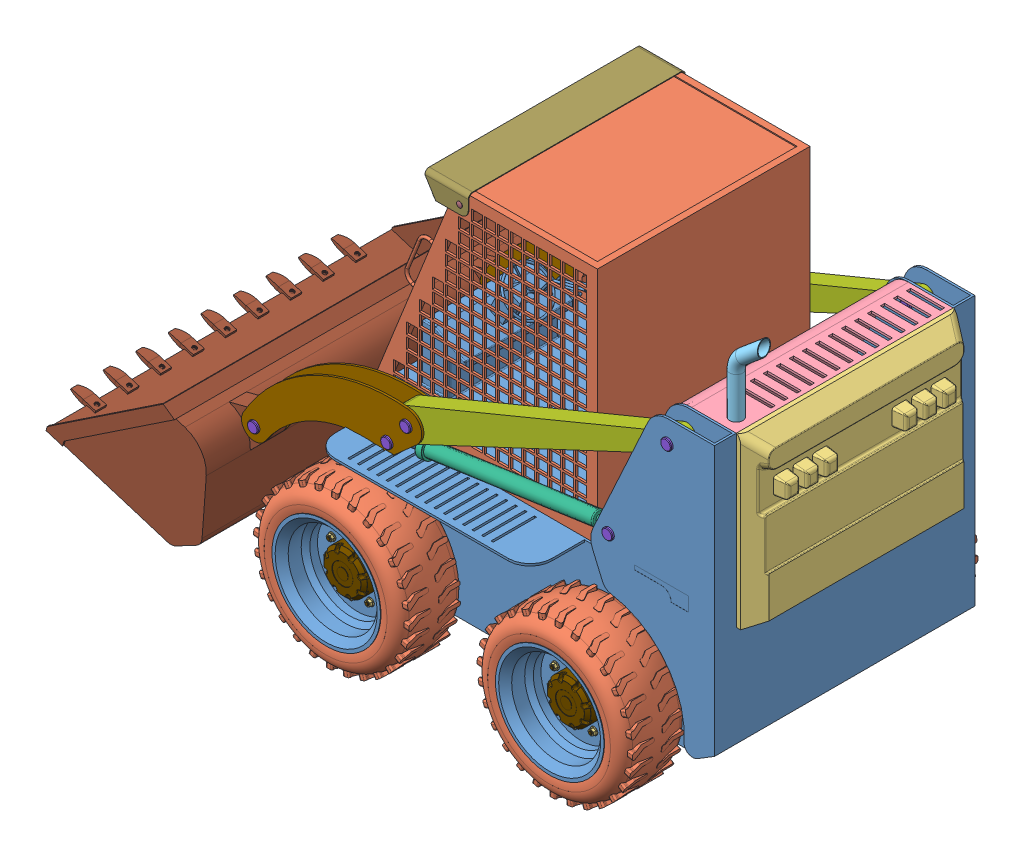
SolidWorks assembly Main Assem, configuration Default. Lengths in mm.
Overall size (3093.47 2132.66 1645.49).
96 component instances, 22 part files, 80 mates.
Components (placement in the parent):
- 1.Body-1: 1.Body [Default] at origin size (1800 1375 1500)
- 2.Cabin-1: 2.Cabin [Default] at (625 600 0) x (0 0 1) z (-1 0 0) size (980 1100 1050)
- 15.Back Support-1: 15.Back Support [Default] at (1150 600 0) size (350 1100 980) (hidden)
- 4.Backcover with light-1: 4.Backcover with light [Default] at (1850 987.5 0) x (0 0 1) z (-1 0 0) size (1000 775 130)
- 14.Backcover-1: 14.Backcover [Default] at (1260.667 789.9683 0) size (539.33 589.21 1000)
- 16.Exhaust Pipe-1: 16.Exhaust Pipe [Default] at (1735 1365 435) size (157.77 388.34 60)
- 11.Cylinder Rod-1: 11.Cylinder Rod [Default] at (830.4266 712.9576 550) x (0.141645 -0.989918 0) z (0 0 1) size (85 940 85)
- 13.LLifting arm-2-1: 13.LLifting arm-2 [Default] at (380.7475 744.6258 550) x (0.915056 0.403326 0) z (-0.403326 0.915056 0) size (1425 80 140)
- 17.Arm Pin-1: 17.Arm Pin [Default] at (1584.0464 1275 550) x (0 0 -1) z (1 0 0) size (120 50 50)
- 17.Arm Pin-2: 17.Arm Pin [Default] at (1313.0114 782.0093 550) x (0 0 1) z (-0.999296 0.037527 0) size (120 50 50)
- 12.Lifting Arm-1: 12.Lifting Arm [Default] at (-320.5164 392.0227 595) x (0.952182 -0.305531 0) z (0 0 1) size (690 680 10)
- 10.Cylinder Rod-1: 10.Cylinder Rod [Default] at (718.9461 697.0061 550) x (0.141645 -0.989918 0) z (0 0 -1) size (60 867.36 80)
- 13.LLifting arm-2-2: 13.LLifting arm-2 [Default] at (380.7475 744.6258 -550) x (0.915056 0.403326 0) z (-0.403326 0.915056 0) size (1425 80 140)
- 11.Cylinder Rod-2: 11.Cylinder Rod [Default] at (830.4266 712.9576 -550) x (0.141645 -0.989918 0) z (0 0 1) size (85 940 85)
- 17.Arm Pin-3: 17.Arm Pin [Default] at (1584.0464 1275 -550) x (0 0 -1) z (1 0 0) size (120 50 50)
- 17.Arm Pin-4: 17.Arm Pin [Default] at (1313.0114 782.0093 -550) x (0 0 -1) z (1 0 0) size (120 50 50)
- 12.Lifting Arm-2: 12.Lifting Arm [Default] at (-320.5164 392.0227 -595) x (0.952182 -0.305531 0) z (0 0 1) size (690 680 10)
- 10.Cylinder Rod-2: 10.Cylinder Rod [Default] at (718.9461 697.0061 -550) x (0.141645 -0.989918 0) z (0 0 -1) size (60 867.36 80)
- 12.Lifting Arm-3: 12.Lifting Arm [Default] at (-320.5164 392.0227 505) x (0.952182 -0.305531 0) z (0 0 1) size (690 680 10)
- 12.Lifting Arm-4: 12.Lifting Arm [Default] at (-320.5164 392.0227 -505) x (0.952182 -0.305531 0) z (0 0 1) size (690 680 10)
- 17.Arm Pin-5: 17.Arm Pin [Default] at (293.4194 636.1187 550) x (0 0 -1) z (1 0 0) size (120 50 50)
- 17.Arm Pin-6: 17.Arm Pin [Default] at (380.7475 744.6258 550) x (0 0 -1) z (1 0 0) size (120 50 50)
- 17.Arm Pin-7: 17.Arm Pin [Default] at (293.4194 636.1187 -550) x (0 0 -1) z (1 0 0) size (120 50 50)
- 17.Arm Pin-8: 17.Arm Pin [Default] at (380.7475 744.6258 -550) x (0 0 -1) z (1 0 0) size (120 50 50)
- 3.Bucket-1: 3.Bucket [Default] at (-804.5027 8.9732 0) x (0 0 1) z (-0.955014 0.296562 0) size (1600 572.07 790.03)
- 17.Arm Pin-9: 17.Arm Pin [Default] at (-320.5164 392.0227 550) x (0 0 1) z (-0.923728 -0.383049 0) size (120 50 50)
- 17.Arm Pin-10: 17.Arm Pin [Default] at (-320.5164 392.0227 -550) x (0 0 -1) z (1 0.000012 0) size (120 50 50)
- 5.Cabin Cap-1: 5.Cabin Cap [Default] at (465 1610 -500) x (0 0 1) z (-1 0 0) size (1000 100 200)
- 18.Cabin Pin-1: 18.Cabin Pin [Default] at (525 1650 484) x (0 0 1) z (-1 0 0) size (20 26 26)
- 18.Cabin Pin-2: 18.Cabin Pin [Default] at (525 1650 -484) x (0 0 -1) z (-0.923728 -0.383049 0) size (20 26 26)
- 22.Sub Assembly Light-1: 22.Sub Assembly Light [Default] at (498.0918 1600 -480) size (120.85 167.94 167.94)
  - 6.Front Light Bulb-1: 6.Front Light Bulb [Default] at (-76.9745 32.3368 62.3068) x (1 0 0) z (0 -0.58962 -0.807681) size (25.36 19 19)
  - 8.Bulb cover-1: 8.Bulb cover [Default] at (-146.4674 32.3368 62.3068) size (29.99 128 128)
  - 7.Front Light Case-1: 7.Front Light Case [Default] at (-13.4674 32.3368 62.3068) x (1 0 0) z (0 0.225273 0.974296) size (100 140 140)
  - 9.Front Light Glass-1: 9.Front Light Glass [Default] at (-84.4674 32.3368 62.3068) x (1 0 0) z (0 0.926957 0.375168) size (33.85 128 128)
- 22.Sub Assembly Light-2: 22.Sub Assembly Light [Default] at (498.0918 1600 355.3864) size (120.85 167.94 167.94)
  - 6.Front Light Bulb-1: 6.Front Light Bulb [Default] at (-76.9745 32.3368 62.3068) x (1 0 0) z (0 -0.58962 -0.807681) size (25.36 19 19)
  - 8.Bulb cover-1: 8.Bulb cover [Default] at (-146.4674 32.3368 62.3068) size (29.99 128 128)
  - 7.Front Light Case-1: 7.Front Light Case [Default] at (-13.4674 32.3368 62.3068) x (1 0 0) z (0 0.225273 0.974296) size (100 140 140)
  - 9.Front Light Glass-1: 9.Front Light Glass [Default] at (-84.4674 32.3368 62.3068) x (1 0 0) z (0 0.926957 0.375168) size (33.85 128 128)
- 23.Tire Assembly-1: 23.Tire Assembly [Default] at (915.573 -35.6641 870.3781) x (0 0 1) z (0.442971 0.896536 0) size (367.75 904.4 904.4)
  - 19.Axle-1: 19.Axle [Default] at (-415.3781 226.5473 319.0258) size (290.35 300 300)
  - 20.Rim-1: 20.Rim [Default] at (-200.3781 226.5473 319.0258) size (300 500 500)
  - 21.Tire-1: 21.Tire [Default] at (-200.3781 226.5473 319.0258) x (1 0 0) z (0 0.311681 0.950187) size (305.49 716.72 716.72)
  - hex flange nut_am-3: hex flange nut_am [B18.2.2.4M - Hex flange nut, M16 x 2 --N] at (-179.3781 266.7195 195.3884) x (0 0.404793 -0.914408) z (1 0 0) size (34.5 34.5 16)
  - hex flange nut_am-13: hex flange nut_am [B18.2.2.4M - Hex flange nut, M16 x 2 --N] at (-179.3781 331.7195 242.6137) x (0 0.86496 -0.501841) z (1 0 0) size (34.5 34.5 16)
  - hex flange nut_am-14: hex flange nut_am [B18.2.2.4M - Hex flange nut, M16 x 2 --N] at (-179.3781 356.5473 319.0258) x (0 0.994742 0.102413) z (1 0 0) size (34.5 34.5 16)
  - hex flange nut_am-15: hex flange nut_am [B18.2.2.4M - Hex flange nut, M16 x 2 --N] at (-179.3781 331.7195 395.4379) x (0 0.744566 0.667549) z (1 0 0) size (34.5 34.5 16)
  - hex flange nut_am-16: hex flange nut_am [B18.2.2.4M - Hex flange nut, M16 x 2 --N] at (-179.3781 266.7195 442.6631) x (0 0.209992 0.977703) z (1 0 0) size (34.5 34.5 16)
  - hex flange nut_am-17: hex flange nut_am [B18.2.2.4M - Hex flange nut, M16 x 2 --N] at (-179.3781 186.3751 442.6631) x (0 -0.404793 0.914408) z (1 0 0) size (34.5 34.5 16)
  - hex flange nut_am-18: hex flange nut_am [B18.2.2.4M - Hex flange nut, M16 x 2 --N] at (-179.3781 121.3751 395.4379) x (0 -0.86496 0.501841) z (1 0 0) size (34.5 34.5 16)
  - hex flange nut_am-19: hex flange nut_am [B18.2.2.4M - Hex flange nut, M16 x 2 --N] at (-179.3781 96.5473 319.0258) x (0 -0.994742 -0.102413) z (1 0 0) size (34.5 34.5 16)
  - hex flange nut_am-20: hex flange nut_am [B18.2.2.4M - Hex flange nut, M16 x 2 --N] at (-179.3781 121.3751 242.6137) x (0 -0.744566 -0.667549) z (1 0 0) size (34.5 34.5 16)
  - hex flange nut_am-21: hex flange nut_am [B18.2.2.4M - Hex flange nut, M16 x 2 --N] at (-179.3781 186.3751 195.3884) x (0 -0.209992 -0.977703) z (1 0 0) size (34.5 34.5 16)
- 23.Tire Assembly-2: 23.Tire Assembly [Default] at (-114.427 -35.6641 870.3781) x (0 0 1) z (0.442971 0.896536 0) size (367.75 904.4 904.4)
  - 19.Axle-1: 19.Axle [Default] at (-415.3781 226.5473 319.0258) size (290.35 300 300)
  - 20.Rim-1: 20.Rim [Default] at (-200.3781 226.5473 319.0258) size (300 500 500)
  - 21.Tire-1: 21.Tire [Default] at (-200.3781 226.5473 319.0258) x (1 0 0) z (0 0.311681 0.950187) size (305.49 716.72 716.72)
  - hex flange nut_am-3: hex flange nut_am [B18.2.2.4M - Hex flange nut, M16 x 2 --N] at (-179.3781 266.7195 195.3884) x (0 0.404793 -0.914408) z (1 0 0) size (34.5 34.5 16)
  - hex flange nut_am-13: hex flange nut_am [B18.2.2.4M - Hex flange nut, M16 x 2 --N] at (-179.3781 331.7195 242.6137) x (0 0.86496 -0.501841) z (1 0 0) size (34.5 34.5 16)
  - hex flange nut_am-14: hex flange nut_am [B18.2.2.4M - Hex flange nut, M16 x 2 --N] at (-179.3781 356.5473 319.0258) x (0 0.994742 0.102413) z (1 0 0) size (34.5 34.5 16)
  - hex flange nut_am-15: hex flange nut_am [B18.2.2.4M - Hex flange nut, M16 x 2 --N] at (-179.3781 331.7195 395.4379) x (0 0.744566 0.667549) z (1 0 0) size (34.5 34.5 16)
  - hex flange nut_am-16: hex flange nut_am [B18.2.2.4M - Hex flange nut, M16 x 2 --N] at (-179.3781 266.7195 442.6631) x (0 0.209992 0.977703) z (1 0 0) size (34.5 34.5 16)
  - hex flange nut_am-17: hex flange nut_am [B18.2.2.4M - Hex flange nut, M16 x 2 --N] at (-179.3781 186.3751 442.6631) x (0 -0.404793 0.914408) z (1 0 0) size (34.5 34.5 16)
  - hex flange nut_am-18: hex flange nut_am [B18.2.2.4M - Hex flange nut, M16 x 2 --N] at (-179.3781 121.3751 395.4379) x (0 -0.86496 0.501841) z (1 0 0) size (34.5 34.5 16)
  - hex flange nut_am-19: hex flange nut_am [B18.2.2.4M - Hex flange nut, M16 x 2 --N] at (-179.3781 96.5473 319.0258) x (0 -0.994742 -0.102413) z (1 0 0) size (34.5 34.5 16)
  - hex flange nut_am-20: hex flange nut_am [B18.2.2.4M - Hex flange nut, M16 x 2 --N] at (-179.3781 121.3751 242.6137) x (0 -0.744566 -0.667549) z (1 0 0) size (34.5 34.5 16)
  - hex flange nut_am-21: hex flange nut_am [B18.2.2.4M - Hex flange nut, M16 x 2 --N] at (-179.3781 186.3751 195.3884) x (0 -0.209992 -0.977703) z (1 0 0) size (34.5 34.5 16)
- 23.Tire Assembly-7: 23.Tire Assembly [Default] at (606.9267 255.0113 -870.3781) x (0 0 -1) z (-0.940812 0.338929 0) size (367.75 904.4 904.4)
  - 19.Axle-1: 19.Axle [Default] at (-415.3781 226.5473 319.0258) size (290.35 300 300)
  - 20.Rim-1: 20.Rim [Default] at (-200.3781 226.5473 319.0258) size (300 500 500)
  - 21.Tire-1: 21.Tire [Default] at (-200.3781 226.5473 319.0258) x (1 0 0) z (0 0.311681 0.950187) size (305.49 716.72 716.72)
  - hex flange nut_am-3: hex flange nut_am [B18.2.2.4M - Hex flange nut, M16 x 2 --N] at (-179.3781 266.7195 195.3884) x (0 0.404793 -0.914408) z (1 0 0) size (34.5 34.5 16)
  - hex flange nut_am-13: hex flange nut_am [B18.2.2.4M - Hex flange nut, M16 x 2 --N] at (-179.3781 331.7195 242.6137) x (0 0.86496 -0.501841) z (1 0 0) size (34.5 34.5 16)
  - hex flange nut_am-14: hex flange nut_am [B18.2.2.4M - Hex flange nut, M16 x 2 --N] at (-179.3781 356.5473 319.0258) x (0 0.994742 0.102413) z (1 0 0) size (34.5 34.5 16)
  - hex flange nut_am-15: hex flange nut_am [B18.2.2.4M - Hex flange nut, M16 x 2 --N] at (-179.3781 331.7195 395.4379) x (0 0.744566 0.667549) z (1 0 0) size (34.5 34.5 16)
  - hex flange nut_am-16: hex flange nut_am [B18.2.2.4M - Hex flange nut, M16 x 2 --N] at (-179.3781 266.7195 442.6631) x (0 0.209992 0.977703) z (1 0 0) size (34.5 34.5 16)
  - hex flange nut_am-17: hex flange nut_am [B18.2.2.4M - Hex flange nut, M16 x 2 --N] at (-179.3781 186.3751 442.6631) x (0 -0.404793 0.914408) z (1 0 0) size (34.5 34.5 16)
  - hex flange nut_am-18: hex flange nut_am [B18.2.2.4M - Hex flange nut, M16 x 2 --N] at (-179.3781 121.3751 395.4379) x (0 -0.86496 0.501841) z (1 0 0) size (34.5 34.5 16)
  - hex flange nut_am-19: hex flange nut_am [B18.2.2.4M - Hex flange nut, M16 x 2 --N] at (-179.3781 96.5473 319.0258) x (0 -0.994742 -0.102413) z (1 0 0) size (34.5 34.5 16)
  - hex flange nut_am-20: hex flange nut_am [B18.2.2.4M - Hex flange nut, M16 x 2 --N] at (-179.3781 121.3751 242.6137) x (0 -0.744566 -0.667549) z (1 0 0) size (34.5 34.5 16)
  - hex flange nut_am-21: hex flange nut_am [B18.2.2.4M - Hex flange nut, M16 x 2 --N] at (-179.3781 186.3751 195.3884) x (0 -0.209992 -0.977703) z (1 0 0) size (34.5 34.5 16)
- 23.Tire Assembly-8: 23.Tire Assembly [Default] at (1649.2952 189.3745 -870.3781) x (0 0 -1) z (-0.869461 0.494002 0) size (367.75 904.4 904.4)
  - 19.Axle-1: 19.Axle [Default] at (-415.3781 226.5473 319.0258) size (290.35 300 300)
  - 20.Rim-1: 20.Rim [Default] at (-200.3781 226.5473 319.0258) size (300 500 500)
  - 21.Tire-1: 21.Tire [Default] at (-200.3781 226.5473 319.0258) x (1 0 0) z (0 0.311681 0.950187) size (305.49 716.72 716.72)
  - hex flange nut_am-3: hex flange nut_am [B18.2.2.4M - Hex flange nut, M16 x 2 --N] at (-179.3781 266.7195 195.3884) x (0 0.404793 -0.914408) z (1 0 0) size (34.5 34.5 16)
  - hex flange nut_am-13: hex flange nut_am [B18.2.2.4M - Hex flange nut, M16 x 2 --N] at (-179.3781 331.7195 242.6137) x (0 0.86496 -0.501841) z (1 0 0) size (34.5 34.5 16)
  - hex flange nut_am-14: hex flange nut_am [B18.2.2.4M - Hex flange nut, M16 x 2 --N] at (-179.3781 356.5473 319.0258) x (0 0.994742 0.102413) z (1 0 0) size (34.5 34.5 16)
  - hex flange nut_am-15: hex flange nut_am [B18.2.2.4M - Hex flange nut, M16 x 2 --N] at (-179.3781 331.7195 395.4379) x (0 0.744566 0.667549) z (1 0 0) size (34.5 34.5 16)
  - hex flange nut_am-16: hex flange nut_am [B18.2.2.4M - Hex flange nut, M16 x 2 --N] at (-179.3781 266.7195 442.6631) x (0 0.209992 0.977703) z (1 0 0) size (34.5 34.5 16)
  - hex flange nut_am-17: hex flange nut_am [B18.2.2.4M - Hex flange nut, M16 x 2 --N] at (-179.3781 186.3751 442.6631) x (0 -0.404793 0.914408) z (1 0 0) size (34.5 34.5 16)
  - hex flange nut_am-18: hex flange nut_am [B18.2.2.4M - Hex flange nut, M16 x 2 --N] at (-179.3781 121.3751 395.4379) x (0 -0.86496 0.501841) z (1 0 0) size (34.5 34.5 16)
  - hex flange nut_am-19: hex flange nut_am [B18.2.2.4M - Hex flange nut, M16 x 2 --N] at (-179.3781 96.5473 319.0258) x (0 -0.994742 -0.102413) z (1 0 0) size (34.5 34.5 16)
  - hex flange nut_am-20: hex flange nut_am [B18.2.2.4M - Hex flange nut, M16 x 2 --N] at (-179.3781 121.3751 242.6137) x (0 -0.744566 -0.667549) z (1 0 0) size (34.5 34.5 16)
  - hex flange nut_am-21: hex flange nut_am [B18.2.2.4M - Hex flange nut, M16 x 2 --N] at (-179.3781 186.3751 195.3884) x (0 -0.209992 -0.977703) z (1 0 0) size (34.5 34.5 16)
Mates (geometry in assembly coordinates):
- Coincident1: coordinate: point of 1.Body-1
- Coincident2: coincident anti-aligned: plane of 1.Body-1 through (0 600 500) normal (0 1 0); plane of 2.Cabin-1 through (100 600 490) normal (0 -1 0)
- Coincident3: coincident aligned: plane of 1.Body-1 through (100 590 500) normal (-1 0 0); plane of 2.Cabin-1 through (100 700 490) normal (-1 0 0)
- Width1: width anti-aligned: plane of 1.Body-1 through (0 0 -500) normal (0 0 -1); plane of 1.Body-1 through (0 0 500) normal (0 0 1); plane of 2.Cabin-1 through (625 600 490) normal (0 0 1); plane of 2.Cabin-1 through (625 600 -490) normal (0 0 -1)
- Coincident4: coincident anti-aligned: plane of 1.Body-1 through (0 600 500) normal (0 1 0); plane of 15.Back Support-1 through (1500 600 490) normal (0 -1 0)
- Coincident7: coincident anti-aligned: plane of 2.Cabin-1 through (1150 600 490) normal (1 0 0); plane of 15.Back Support-1 through (1150 600 490) normal (-1 0 0)
- Width3: width anti-aligned: plane of 2.Cabin-1 through (625 600 490) normal (0 0 1); plane of 2.Cabin-1 through (625 600 -490) normal (0 0 -1); plane of 15.Back Support-1 through (1150 600 -490) normal (0 0 -1); plane of 15.Back Support-1 through (1150 600 490) normal (0 0 1)
- Coincident8: coincident anti-aligned: plane of 1.Body-1 through (0 600 500) normal (0 1 0); plane of 4.Backcover with light-1 through (1800 600 -500) normal (0 -1 0)
- Coincident9: coincident anti-aligned: plane of 1.Body-1 through (1698.9717 119.9359 500) normal (0 0 -1); plane of 4.Backcover with light-1 through (1800 600 500) normal (0 0 1)
- Coincident10: coincident anti-aligned: plane of 1.Body-1 through (1800 600 500) normal (1 0 0); plane of 4.Backcover with light-1 through (1800 987.5 0) normal (-1 0 0)
- Coincident12: coincident anti-aligned: plane of 1.Body-1 through (1698.9717 119.9359 500) normal (0 0 -1); plane of 14.Backcover-1 through (1594.05 1275 500) normal (0 0 1)
- Coincident16: coincident anti-aligned: plane of 4.Backcover with light-1 through (1800 987.5 0) normal (-1 0 0); plane of 14.Backcover-1 through (1800 1375 500) normal (1 0 0)
- Concentric1: concentric aligned: cylinder of 14.Backcover-1 through (1735 785.7865 435) axis (0 1 0) radius 30; cylinder of 16.Exhaust Pipe-1 through (1735 1365 435) axis (0 1 0) radius 30
- Coincident17: coincident aligned: plane of 14.Backcover-1 through (1594.05 1365 500) normal (0 -1 0); plane of 16.Exhaust Pipe-1 through (1735 1365 435) normal (0 -1 0)
- Coincident18: coincident aligned: line of 4.Backcover with light-1 through (1800 1375 500) axis (0 0 -1); line of 14.Backcover-1 through (1800 1375 500) axis (0 0 -1)
- Parallel4: parallel aligned: plane of 1.Body-1 through (1800 600 500) normal (1 0 0); plane of 16.Exhaust Pipe-1 through (1862.7722 1753.3435 405) normal (1 0 0)
- Coincident20: coincident anti-aligned: plane of 1.Body-1 through (1698.9717 119.9359 590) normal (0 0 -1); plane of 11.Cylinder Rod-1 through (1313.0114 782.0093 590) normal (0 0 1)
- Concentric2: concentric anti-aligned: cylinder of 1.Body-1 through (1313.0114 782.0093 -600) axis (0 0 1) radius 15; cylinder of 11.Cylinder Rod-1 through (1313.0114 782.0093 590) axis (0 0 -1) radius 15
- Coincident21: coincident anti-aligned: plane of 1.Body-1 through (1698.9717 119.9359 510) normal (0 0 1); plane of 13.LLifting arm-2-1 through (380.7475 744.6258 510) normal (0 0 -1)
- Concentric3: concentric aligned: cylinder of 1.Body-1 through (1584.0464 1275 -600) axis (0 0 1) radius 20; cylinder of 13.LLifting arm-2-1 through (1584.0464 1275 510) axis (0 0 1) radius 20
- Concentric4: concentric anti-aligned: cylinder of 13.LLifting arm-2-1 through (1584.0464 1275 510) axis (0 0 1) radius 20; cylinder of 17.Arm Pin-1 through (1584.0464 1275 490) axis (0 0 -1) radius 15
- Coincident23: coincident anti-aligned: plane of 1.Body-1 through (1698.9717 119.9359 600) normal (0 0 1); plane of 17.Arm Pin-1 through (1584.0464 1290 600) normal (0 0 -1)
- Concentric5: concentric anti-aligned: cylinder of 11.Cylinder Rod-1 through (1313.0114 782.0093 590) axis (0 0 -1) radius 15; cylinder of 17.Arm Pin-2 through (1313.0114 782.0093 610) axis (0 0 1) radius 15
- Coincident24: coincident anti-aligned: plane of 1.Body-1 through (1698.9717 119.9359 600) normal (0 0 1); plane of 17.Arm Pin-2 through (1313.5743 796.9988 600) normal (0 0 -1)
- Concentric6: concentric anti-aligned: cylinder of 13.LLifting arm-2-1 through (380.7475 744.6258 510) axis (0 0 1) radius 25; cylinder of 12.Lifting Arm-1 through (380.7475 744.6258 600) axis (0 0 -1) radius 20
- Concentric7: concentric anti-aligned: cylinder of 11.Cylinder Rod-1 through (1214.0197 767.8449 550) axis (-0.989918 -0.141645 0) radius 20; cylinder of 10.Cylinder Rod-1 through (315.5547 639.2859 550) axis (0.989918 0.141645 0) radius 20
- Concentric9: concentric anti-aligned: cylinder of 12.Lifting Arm-1 through (293.4194 636.1187 600) axis (0 0 -1) radius 15; cylinder of 10.Cylinder Rod-1 through (293.4194 636.1187 510) axis (0 0 1) radius 15
- Coincident26: coincident anti-aligned: plane of 1.Body-1 through (1698.9717 119.9359 -590) normal (0 0 1); plane of 13.LLifting arm-2-2 through (380.7475 744.6258 -590) normal (0 0 -1)
- Concentric10: concentric aligned: cylinder of 1.Body-1 through (1584.0464 1275 -600) axis (0 0 1) radius 20; cylinder of 13.LLifting arm-2-2 through (1584.0464 1275 -590) axis (0 0 1) radius 20
- Coincident27: coincident anti-aligned: plane of 1.Body-1 through (1698.9717 119.9359 -590) normal (0 0 1); plane of 11.Cylinder Rod-2 through (1313.0114 782.0093 -590) normal (0 0 -1)
- Concentric11: concentric anti-aligned: cylinder of 1.Body-1 through (1313.0114 782.0093 -600) axis (0 0 1) radius 15; cylinder of 11.Cylinder Rod-2 through (1313.0114 782.0093 -510) axis (0 0 -1) radius 15
- Concentric12: concentric anti-aligned: cylinder of 13.LLifting arm-2-2 through (1584.0464 1275 -590) axis (0 0 1) radius 20; cylinder of 17.Arm Pin-3 through (1584.0464 1275 -610) axis (0 0 -1) radius 15
- Coincident28: coincident anti-aligned: plane of 1.Body-1 through (1698.9717 119.9359 -600) normal (0 0 -1); plane of 17.Arm Pin-3 through (1584.0464 1290 -600) normal (0 0 1)
- Concentric13: concentric aligned: cylinder of 11.Cylinder Rod-2 through (1313.0114 782.0093 -510) axis (0 0 -1) radius 15; cylinder of 17.Arm Pin-4 through (1313.0114 782.0093 -610) axis (0 0 -1) radius 15
- Coincident29: coincident anti-aligned: plane of 1.Body-1 through (1698.9717 119.9359 -600) normal (0 0 -1); plane of 17.Arm Pin-4 through (1313.0114 797.0093 -600) normal (0 0 1)
- Concentric14: concentric anti-aligned: cylinder of 13.LLifting arm-2-2 through (380.7475 744.6258 -590) axis (0 0 1) radius 25; cylinder of 12.Lifting Arm-2 through (380.7475 744.6258 -590) axis (0 0 -1) radius 20
- Concentric15: concentric anti-aligned: cylinder of 11.Cylinder Rod-2 through (1214.0197 767.8449 -550) axis (-0.989918 -0.141645 0) radius 20; cylinder of 10.Cylinder Rod-2 through (315.5547 639.2859 -550) axis (0.989918 0.141645 0) radius 20
- Coincident30: coincident anti-aligned: plane of 12.Lifting Arm-2 through (186.0821 52.2317 -590) normal (0 0 1); plane of 10.Cylinder Rod-2 through (293.4194 636.1187 -590) normal (0 0 -1)
- Concentric17: concentric anti-aligned: cylinder of 13.LLifting arm-2-1 through (380.7475 744.6258 510) axis (0 0 1) radius 25; cylinder of 12.Lifting Arm-3 through (380.7475 744.6258 510) axis (0 0 -1) radius 20
- Coincident31: coincident anti-aligned: plane of 13.LLifting arm-2-1 through (380.7475 744.6258 510) normal (0 0 -1); plane of 12.Lifting Arm-3 through (186.0821 52.2317 510) normal (0 0 1)
- Concentric18: concentric anti-aligned: cylinder of 10.Cylinder Rod-1 through (293.4194 636.1187 510) axis (0 0 1) radius 15; cylinder of 12.Lifting Arm-3 through (293.4194 636.1187 510) axis (0 0 -1) radius 15
- Coincident32: coincident anti-aligned: plane of 13.LLifting arm-2-1 through (380.7475 744.6258 590) normal (0 0 1); plane of 12.Lifting Arm-1 through (186.0821 52.2317 590) normal (0 0 -1)
- Concentric20: concentric anti-aligned: cylinder of 12.Lifting Arm-2 through (293.4194 636.1187 -590) axis (0 0 -1) radius 15; cylinder of 10.Cylinder Rod-2 through (293.4194 636.1187 -590) axis (0 0 1) radius 15
- Coincident33: coincident anti-aligned: plane of 13.LLifting arm-2-2 through (380.7475 744.6258 -510) normal (0 0 1); plane of 12.Lifting Arm-4 through (186.0821 52.2317 -510) normal (0 0 -1)
- Concentric21: concentric anti-aligned: cylinder of 13.LLifting arm-2-2 through (380.7475 744.6258 -590) axis (0 0 1) radius 25; cylinder of 12.Lifting Arm-4 through (380.7475 744.6258 -500) axis (0 0 -1) radius 20
- Concentric22: concentric anti-aligned: cylinder of 10.Cylinder Rod-2 through (293.4194 636.1187 -590) axis (0 0 1) radius 15; cylinder of 12.Lifting Arm-4 through (293.4194 636.1187 -500) axis (0 0 -1) radius 15
- Concentric23: concentric anti-aligned: cylinder of 13.LLifting arm-2-1 through (380.7475 744.6258 510) axis (0 0 1) radius 25; cylinder of 17.Arm Pin-6 through (380.7475 744.6258 490) axis (0 0 -1) radius 15
- Coincident34: coincident anti-aligned: plane of 12.Lifting Arm-1 through (186.0821 52.2317 600) normal (0 0 1); plane of 17.Arm Pin-6 through (380.7475 759.6258 600) normal (0 0 -1)
- Concentric24: concentric anti-aligned: cylinder of 10.Cylinder Rod-1 through (293.4194 636.1187 510) axis (0 0 1) radius 15; cylinder of 17.Arm Pin-5 through (293.4194 636.1187 490) axis (0 0 -1) radius 15
- Coincident35: coincident anti-aligned: plane of 12.Lifting Arm-1 through (186.0821 52.2317 600) normal (0 0 1); plane of 17.Arm Pin-5 through (293.4194 651.1187 600) normal (0 0 -1)
- Concentric25: concentric anti-aligned: cylinder of 13.LLifting arm-2-2 through (380.7475 744.6258 -590) axis (0 0 1) radius 25; cylinder of 17.Arm Pin-8 through (380.7475 744.6258 -610) axis (0 0 -1) radius 15
- Coincident36: coincident anti-aligned: plane of 12.Lifting Arm-2 through (186.0821 52.2317 -600) normal (0 0 -1); plane of 17.Arm Pin-8 through (380.7475 759.6258 -600) normal (0 0 1)
- Concentric26: concentric anti-aligned: cylinder of 10.Cylinder Rod-2 through (293.4194 636.1187 -590) axis (0 0 1) radius 15; cylinder of 17.Arm Pin-7 through (293.4194 636.1187 -610) axis (0 0 -1) radius 15
- Coincident37: coincident anti-aligned: plane of 12.Lifting Arm-2 through (186.0821 52.2317 -600) normal (0 0 -1); plane of 17.Arm Pin-7 through (293.4194 651.1187 -600) normal (0 0 1)
- Concentric30: concentric aligned: cylinder of 12.Lifting Arm-4 through (-320.5164 392.0227 -500) axis (0 0 -1) radius 20; cylinder of 3.Bucket-1 through (-320.5164 392.0227 -510) axis (0 0 -1) radius 20
- Coincident43: coincident anti-aligned: plane of 12.Lifting Arm-4 through (186.0821 52.2317 -510) normal (0 0 -1); plane of 3.Bucket-1 through (-489.1525 287.3238 -510) normal (0 0 1)
- Concentric31: concentric anti-aligned: cylinder of 12.Lifting Arm-1 through (-320.5164 392.0227 600) axis (0 0 -1) radius 20; cylinder of 3.Bucket-1 through (-320.5164 392.0227 510) axis (0 0 1) radius 20
- Coincident45: coincident anti-aligned: plane of 12.Lifting Arm-1 through (186.0821 52.2317 590) normal (0 0 -1); plane of 3.Bucket-1 through (-489.1525 287.3238 590) normal (0 0 1)
- Concentric32: concentric aligned: cylinder of 17.Arm Pin-9 through (-320.5164 392.0227 610) axis (0 0 1) radius 15; cylinder of 3.Bucket-1 through (-320.5164 392.0227 510) axis (0 0 1) radius 20
- Coincident46: coincident anti-aligned: plane of 12.Lifting Arm-3 through (186.0821 52.2317 500) normal (0 0 -1); plane of 17.Arm Pin-9 through (-326.2621 405.8786 500) normal (0 0 1)
- Concentric33: concentric aligned: cylinder of 3.Bucket-1 through (-320.5164 392.0227 -510) axis (0 0 -1) radius 20; cylinder of 17.Arm Pin-10 through (-320.5164 392.0227 -610) axis (0 0 -1) radius 15
- Coincident47: coincident anti-aligned: plane of 12.Lifting Arm-2 through (186.0821 52.2317 -600) normal (0 0 -1); plane of 17.Arm Pin-10 through (-320.5166 407.0227 -600) normal (0 0 1)
- Concentric34: concentric aligned: cylinder of 2.Cabin-1 through (525 1650 -490) axis (0 0 1) radius 10; cylinder of 5.Cabin Cap-1 through (525 1650 -500) axis (0 0 1) radius 10
- Width4: width anti-aligned: plane of 2.Cabin-1 through (625 600 490) normal (0 0 1); plane of 5.Cabin Cap-1 through (625 600 -490) normal (0 0 -1); plane of 2.Cabin-1 through (365 1610 -500) normal (0 0 -1); plane of 5.Cabin Cap-1 through (365 1690 500) normal (0 0 1)
- Concentric35: concentric aligned: cylinder of 2.Cabin-1 through (525 1650 -490) axis (0 0 1) radius 10; cylinder of 5.Cabin Cap-1 through (525 1650 -500) axis (0 0 1) radius 10
- Parallel8: parallel anti-aligned: plane of 2.Cabin-1 through (1150 1700 490) normal (0 1 0); plane of 5.Cabin Cap-1 through (365 1707 -477) normal (0 -1 0)
- Concentric36: concentric anti-aligned: cylinder of 5.Cabin Cap-1 through (525 1650 -500) axis (0 0 1) radius 10; cylinder of 18.Cabin Pin-1 through (525 1650 484) axis (0 0 -1) radius 10
- Coincident50: coincident anti-aligned: plane of 5.Cabin Cap-1 through (365 1690 500) normal (0 0 1); plane of 18.Cabin Pin-1 through (525 1660 500) normal (0 0 -1)
- Concentric37: concentric aligned: cylinder of 5.Cabin Cap-1 through (525 1650 -500) axis (0 0 1) radius 10; cylinder of 18.Cabin Pin-2 through (525 1650 -484) axis (0 0 1) radius 10
- Coincident51: coincident anti-aligned: plane of 5.Cabin Cap-1 through (365 1610 -500) normal (0 0 -1); plane of 18.Cabin Pin-2 through (528.8305 1640.7627 -500) normal (0 0 1)
- Distance1: distance = 480 mm aligned: plane of 22.Sub Assembly Light-1 through (498.0918 1600 -480) normal (0 0 1)
- Distance2: distance = 100 mm aligned: plane of 22.Sub Assembly Light-1 through (498.0918 1600 -480) normal (0 1 0); plane of 2.Cabin-1 through (1150 1700 490) normal (0 1 0)
- Concentric38: concentric anti-aligned: cylinder of 1.Body-1 through (1260 150 500) axis (0 0 -1) radius 50; cylinder of 23.Tire Assembly-1/19.Axle-1 through (1260 150 745) axis (0 0 1) radius 40
- Distance3: distance = 20 mm anti-aligned: plane of 23.Tire Assembly-1/20.Rim-1 through (1484.134 39.2572 520) normal (0 0 -1); plane of 1.Body-1 through (0 0 500) normal (0 0 1)
- Concentric39: concentric anti-aligned: cylinder of 1.Body-1 through (230 150 500) axis (0 0 -1) radius 50; cylinder of 23.Tire Assembly-2/19.Axle-1 through (230 150 745) axis (0 0 1) radius 40
- Distance4: distance = 20 mm anti-aligned: plane of 23.Tire Assembly-2/20.Rim-1 through (454.134 39.2572 520) normal (0 0 -1); plane of 1.Body-1 through (0 0 500) normal (0 0 1)
- Concentric40: concentric: cylinder of 1.Body-1 through (1260 150 500) axis (0 0 -1) radius 50; cylinder of 23.Tire Assembly-8/19.Axle-1 through (1260 150 -745) axis (0 0 -1) radius 40
- Concentric41: concentric: cylinder of 1.Body-1 through (230 150 500) axis (0 0 -1) radius 50; cylinder of 23.Tire Assembly-7/19.Axle-1 through (230 150 -745) axis (0 0 -1) radius 40
- Distance5: distance = 20 mm anti-aligned: plane of 23.Tire Assembly-8/20.Rim-1 through (1136.4994 -67.3652 -520) normal (0 0 1); plane of 1.Body-1 through (0 0 -500) normal (0 0 -1)
- Distance6: distance = 20 mm anti-aligned: plane of 23.Tire Assembly-7/20.Rim-1 through (145.2678 -85.203 -520) normal (0 0 1); plane of 1.Body-1 through (0 0 -500) normal (0 0 -1)
